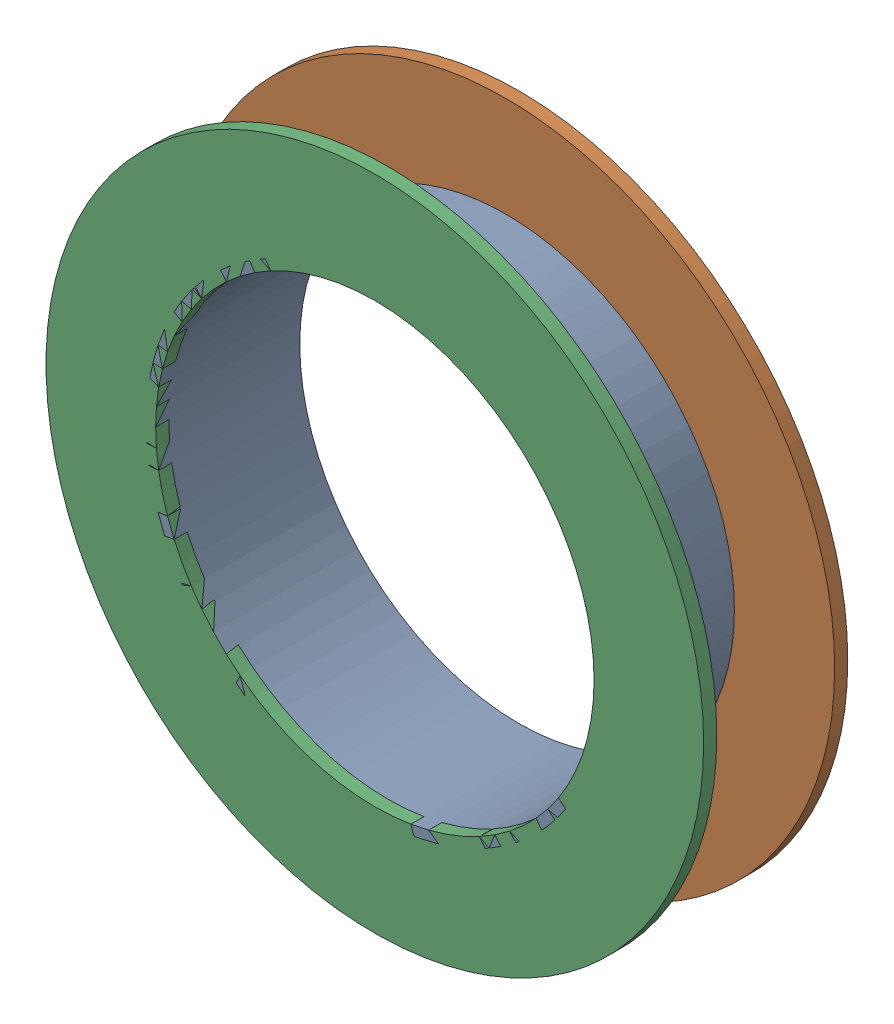
SolidWorks assembly Pad U1-2(28.178mm,59.438mm) on Multi-Layer, configuration Predeterminado. Lengths in mm.
Overall size (1.79 1.79 0.39).
6 component instances, 2 part files, 0 mates.
Components (placement in the parent):
- Pad Hole-1: Pad Hole [Predeterminado] at (28.1784 59.4378 -0.4013) size (1.24 1.24 0.39)
  - Pad Hole-Part-1-1: Pad Hole-Part-1 [Predeterminado] at origin size (1.24 1.24 0.39)
- Top Layer-1: Top Layer [Predeterminado] at (28.1784 59.4378 -0.4013) size (1.79 1.79 0.04)
  - Top Layer-Part-1-1: Top Layer-Part-1 [Predeterminado] at origin size (1.79 1.79 0.04)
- Top Layer-2: Top Layer [Predeterminado] at (28.1784 59.4378 -0.0457) size (1.79 1.79 0.04)
  - Top Layer-Part-1-1: Top Layer-Part-1 [Predeterminado] at origin size (1.79 1.79 0.04)
